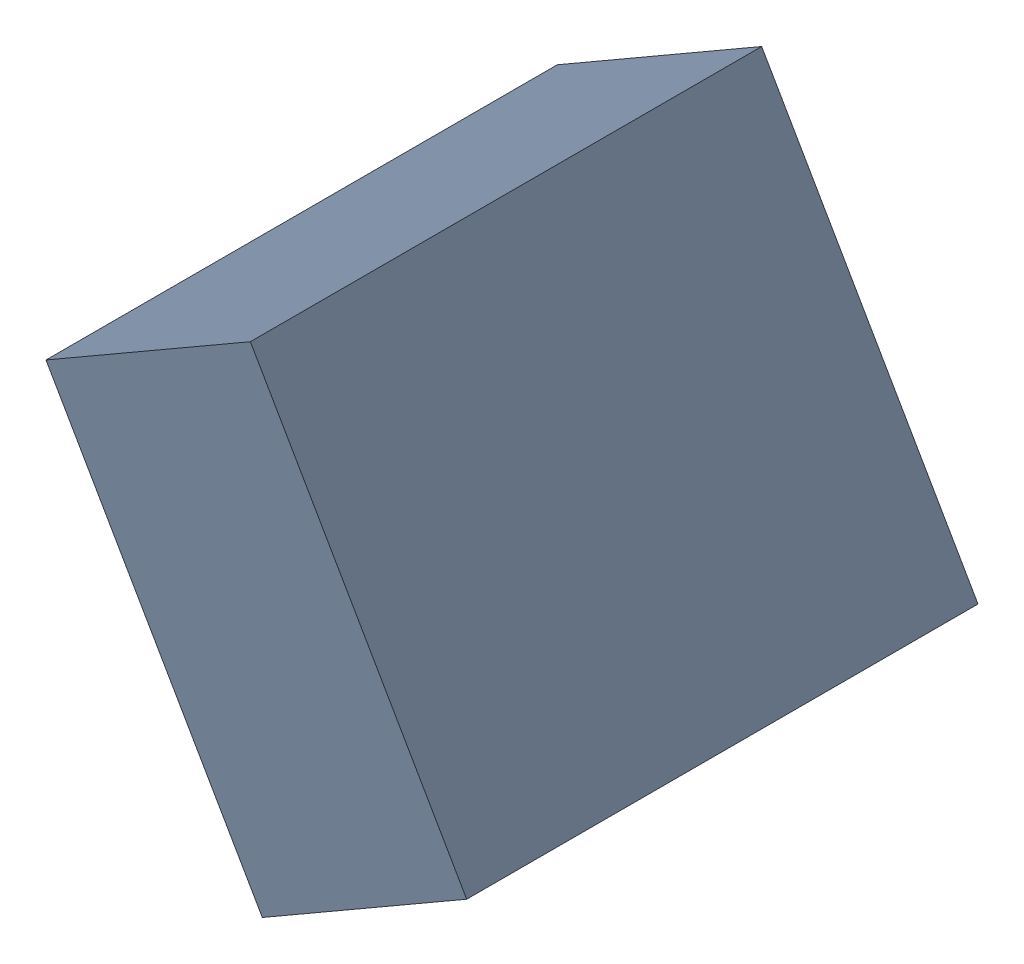
SolidWorks assembly C28_TDA2, configuration Standard. Lengths in mm.
Overall size (1.07 1.25 1.3).
2 component instances, 1 part files, 0 mates.
Components (placement in the parent):
- 885543192-1: 885543192 [Standard] at (47.968 31.1121 0) size (1.07 1.25 1.3)
  - Extruded_27-1: Extruded_27 [Standard] at origin size (1.07 1.25 1.3)
